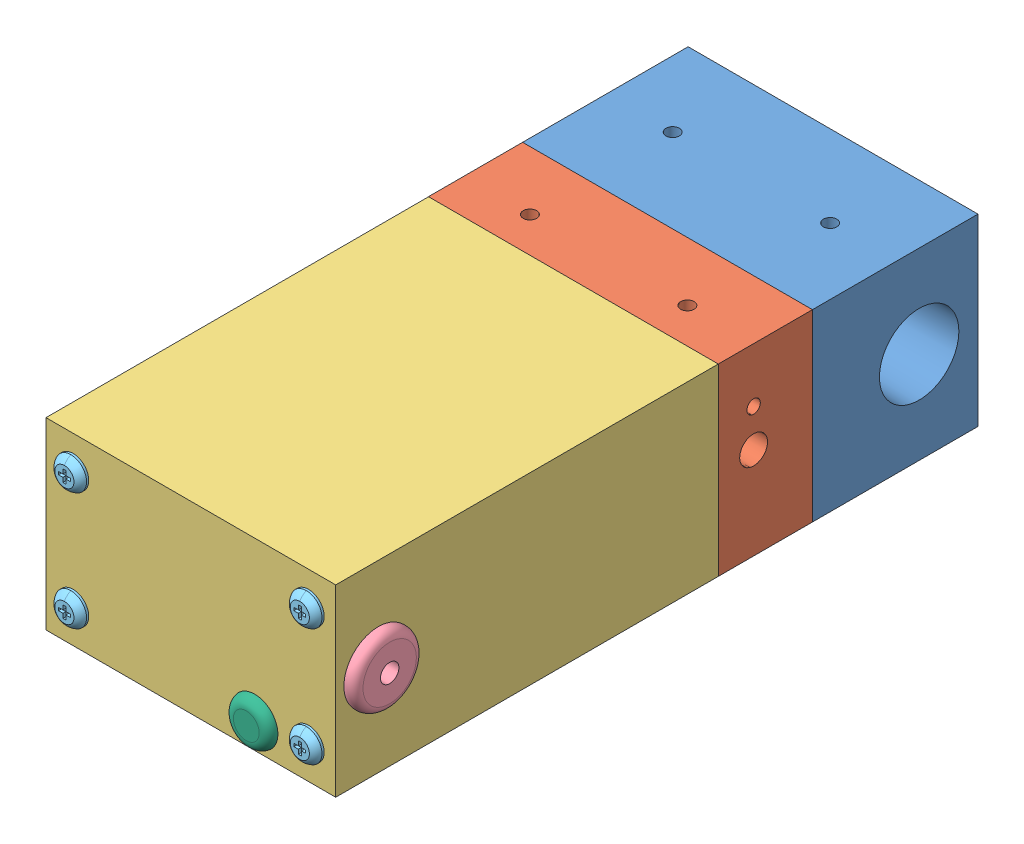
SolidWorks assembly HFR-14 REL, configuration Default. Lengths in mm.
Overall size (51.99 31.75 112.37).
9 component instances, 6 part files, 17 mates.
Components (placement in the parent):
- KP040703-14 Rev B-1: KP040703-14 Rev B [Default] at origin size (50.04 31.75 28.57)
- KP081503 Rev X1-1: KP081503 Rev X1 [Default] at (0 0 44.831) size (50.04 31.75 16.26)
- KP081903REVX2-2 Short-1: KP081903REVX2-2 Short [Default] at (0.0254 31.75 44.831) x (1 0 0) z (0 0 -1) size (50.01 31.75 66.04)
- 9600K17 Rubber Grommet-1: 9600K17 Rubber Grommet [Default] at (51.9862 15.875 103.505) x (0 1 0) z (0 0 1) size (11.98 5.52 11.98)
- 128667-01 Screw, Button head, 4-40x.5, ss-1-1: 128667-01 Screw, Button head, 4-40x.5, ss-1 [Default] at (4.699 5.715 112.2102) x (1 0 0) z (0 -1 0) size (5.41 12.7 5.41)
- 128667-01 Screw, Button head, 4-40x.5, ss-1-2: 128667-01 Screw, Button head, 4-40x.5, ss-1 [Default] at (45.339 26.035 112.2102) x (1 0 0) z (0 -1 0) size (5.41 12.7 5.41)
- 128667-01 Screw, Button head, 4-40x.5, ss-1-3: 128667-01 Screw, Button head, 4-40x.5, ss-1 [Default] at (45.339 5.715 112.2102) x (1 0 0) z (0 -1 0) size (5.41 12.7 5.41)
- 128667-01 Screw, Button head, 4-40x.5, ss-1-4: 128667-01 Screw, Button head, 4-40x.5, ss-1 [Default] at (4.699 26.035 112.2102) x (1 0 0) z (0 -1 0) size (5.41 12.7 5.41)
- 85985K12-1: 85985K12 [Default] at (36.068 4.445 104.3559) size (7.96 7.96 7.99)
Mates (geometry in assembly coordinates):
- Concentric2: concentric anti-aligned: cylinder of KP081903REVX2-2 Short-1 through (50.038 4.8143 103.505) axis (-1 0 0) radius 2.6924; cylinder of 9600K17 Rubber Grommet-1 through (51.9862 4.8143 103.505) axis (1 0 0) radius 1.5876
- Coincident6: coincident anti-aligned: plane of KP081903REVX2-2 Short-1 through (50.038 20.6893 110.871) normal (1 0 0); plane of 9600K17 Rubber Grommet-1 through (50.038 1.0248 103.505) normal (-1 0 0)
- Concentric7: concentric aligned: cylinder of KP081903REVX2-2 Short-1 through (4.699 -5.3457 44.83) axis (0 0 1) radius 1.5875; cylinder of 128667-01 Screw, Button head, 4-40x.5, ss-1-1 through (4.699 -5.3457 100.0172) axis (0 0 1) radius 1.4224
- Concentric8: concentric aligned: cylinder of 128667-01 Screw, Button head, 4-40x.5, ss-1-4 through (4.699 14.9743 100.0172) axis (0 0 1) radius 1.4224; cylinder of KP081903REVX2-2 Short-1 through (4.699 14.9743 44.83) axis (0 0 1) radius 1.5875
- Concentric9: concentric aligned: cylinder of 128667-01 Screw, Button head, 4-40x.5, ss-1-3 through (45.339 -5.3457 100.0172) axis (0 0 1) radius 1.4224; cylinder of KP081903REVX2-2 Short-1 through (45.339 -5.3457 44.83) axis (0 0 1) radius 1.5875
- Concentric10: concentric aligned: cylinder of KP081903REVX2-2 Short-1 through (45.339 14.9743 44.83) axis (0 0 1) radius 1.5875; cylinder of 128667-01 Screw, Button head, 4-40x.5, ss-1-2 through (45.339 14.9743 100.0172) axis (0 0 1) radius 1.4224
- Coincident7: coincident anti-aligned: plane of KP081903REVX2-2 Short-1 through (0.0254 -11.0607 110.871) normal (0 0 1); plane of 128667-01 Screw, Button head, 4-40x.5, ss-1-3 through (42.6014 -2.6081 110.871) normal (0 0 -1)
- Coincident8: coincident anti-aligned: plane of KP081903REVX2-2 Short-1 through (0.0254 -11.0607 110.871) normal (0 0 1); plane of 128667-01 Screw, Button head, 4-40x.5, ss-1-2 through (42.6014 17.7119 110.871) normal (0 0 -1)
- Coincident9: coincident anti-aligned: plane of KP081903REVX2-2 Short-1 through (0.0254 -11.0607 110.871) normal (0 0 1); plane of 128667-01 Screw, Button head, 4-40x.5, ss-1-1 through (1.9614 -2.6081 110.871) normal (0 0 -1)
- Coincident10: coincident anti-aligned: plane of KP081903REVX2-2 Short-1 through (0.0254 -11.0607 110.871) normal (0 0 1); plane of 128667-01 Screw, Button head, 4-40x.5, ss-1-4 through (1.9614 17.7119 110.871) normal (0 0 -1)
- Coincident11: coincident anti-aligned: plane of KP081903REVX2-2 Short-1 through (0.0254 -11.0607 110.871) normal (0 0 1); plane of 85985K12-1 through (36.068 4.445 110.871) normal (0 0 -1)
- Coincident12: coincident aligned: plane of KP040703-14 Rev B-1 through (50.038 0 28.575) normal (1 0 0); plane of KP081503 Rev X1-1 through (50.038 0 28.575) normal (1 0 0)
- Coincident13: coincident aligned: plane of KP040703-14 Rev B-1 through (0 0 28.575) normal (0 -1 0); plane of KP081503 Rev X1-1 through (0 0 28.575) normal (0 -1 0)
- Coincident14: coincident anti-aligned: plane of KP040703-14 Rev B-1 through (0 31.75 28.575) normal (0 0 1); plane of KP081503 Rev X1-1 through (0 31.75 28.575) normal (0 0 -1)
- Coincident15: coincident anti-aligned: plane of KP081503 Rev X1-1 through (0 31.75 44.831) normal (0 0 1); plane of KP081903REVX2-2 Short-1 through (0.0254 0 44.831) normal (0 0 -1)
- Coincident16: coincident aligned: plane of KP081503 Rev X1-1 through (50.038 0 28.575) normal (1 0 0); plane of KP081903REVX2-2 Short-1 through (50.038 31.75 110.871) normal (1 0 0)
- Coincident17: coincident aligned: plane of KP081503 Rev X1-1 through (0 0 28.575) normal (0 -1 0); plane of KP081903REVX2-2 Short-1 through (0.0254 0 110.871) normal (0 -1 0)
